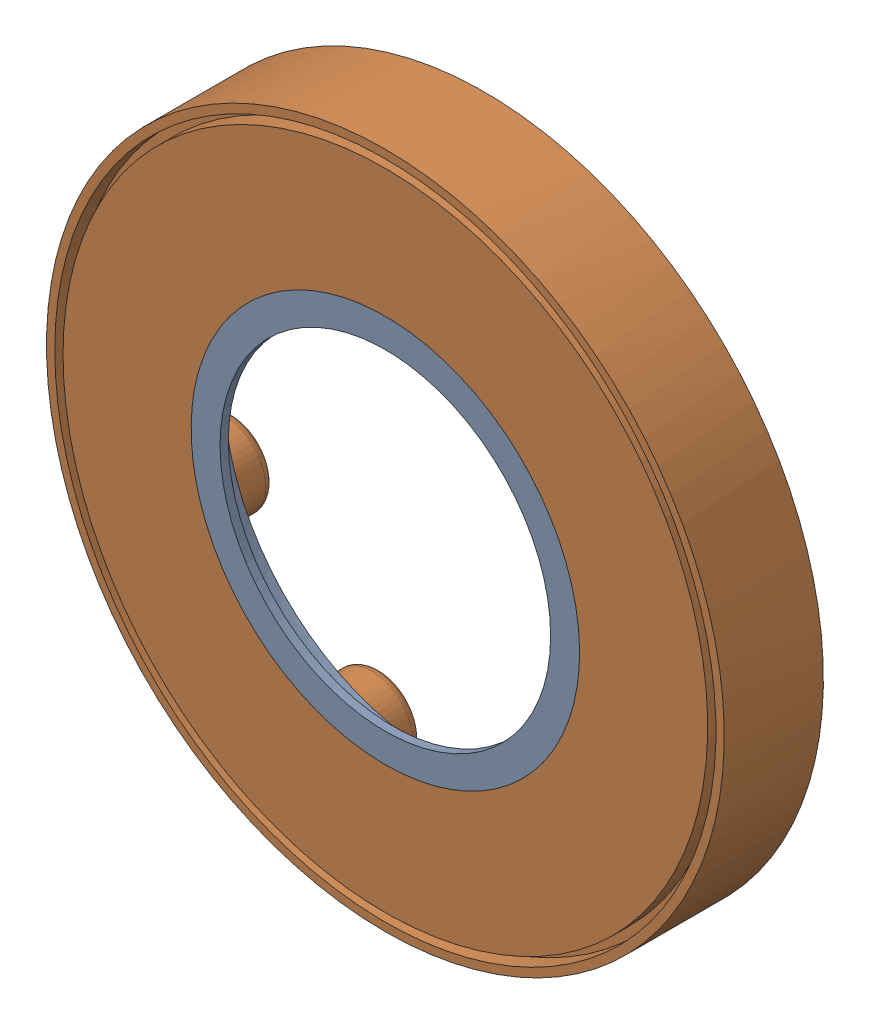
SolidWorks assembly Bracket assembly, configuration Default. Lengths in mm.
Overall size (82 82 12).
2 component instances, 2 part files, 2 mates.
Components (placement in the parent):
- Bracket-1: Bracket [Default] at (-59.0652 3.8741 25.5359) size (79.4 79.4 6)
- Bracket holder-1: Bracket holder [Default] at (-59.0652 3.8741 26.5359) x (-1 0 0) z (0 1 0) size (82 12 82)
Mates (geometry in assembly coordinates):
- Coincident1: coincident anti-aligned: circle of Bracket-1; circle of Bracket holder-1
- Concentric1: concentric aligned: cylinder of Bracket-1 through (-24.0652 3.8741 25.5359) axis (0 0 1) radius 1.9; cylinder of Bracket holder-1 through (-24.0652 3.8741 24.5359) axis (0 0 1) radius 1.9
